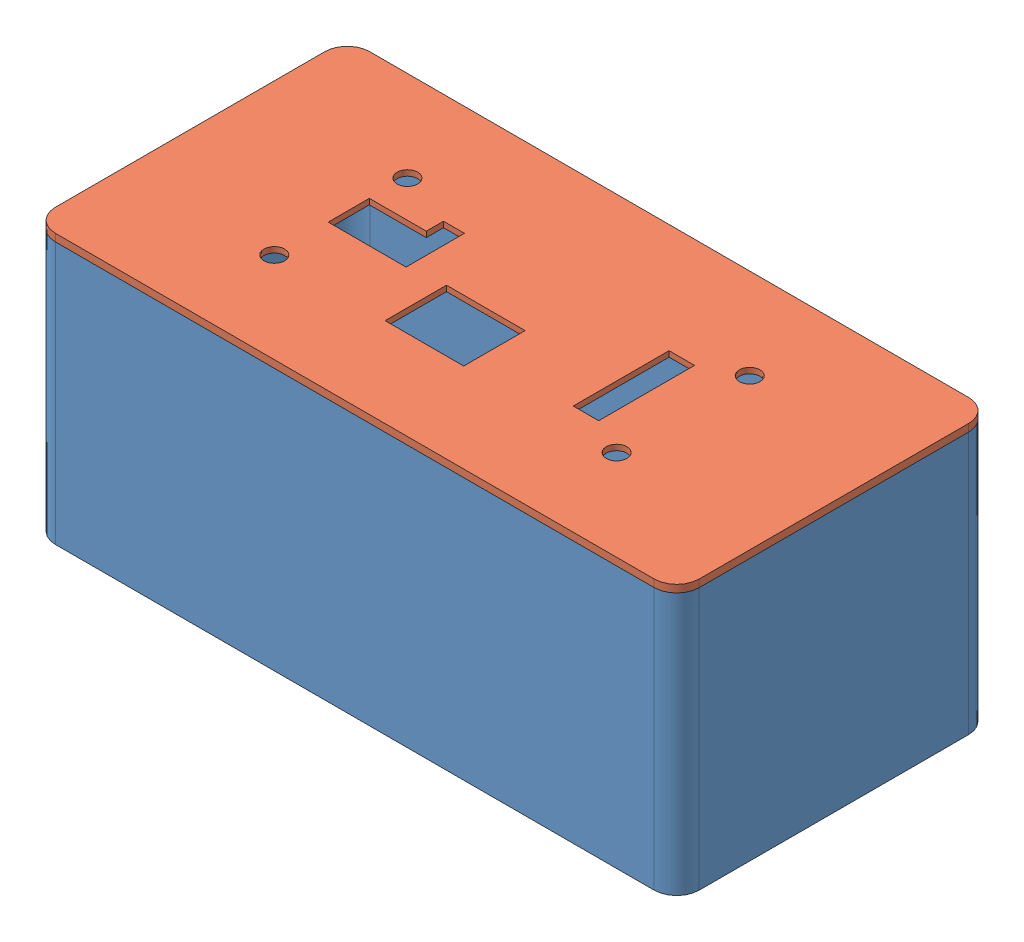
SolidWorks assembly CtrlBoard_Enclosure, configuration Default. Lengths in mm.
Overall size (86 36 42).
2 component instances, 2 part files, 4 mates.
Components (placement in the parent):
- CtrlBoard_enclosure_bottomassm-1: CtrlBoard_enclosure_bottomassm [Default] at (-11.0017 23.4167 89.7591) size (86 35 42)
- CtrlBoard_enclosure_top^CtrlBoard_Enclosure-1: CtrlBoard_enclosure_top^CtrlBoard_Enclosure [Default] at (-11.0017 58.4167 89.7591) x (1 0 0) z (0 1 0) size (86 42 2) (virtual)
Mates (geometry in assembly coordinates):
- InPlace1: in place: plane of CtrlBoard_enclosure_bottomassm-1 through (-11.0017 58.4167 89.7591) normal (0 1 0); plane of ? through (0 58.4167 0) normal (0 1 0); moOrthogonalPlaneRef_w of CtrlBoard_enclosure_bottomassm-1 through (-11.0017 58.4167 89.7591) normal (0 1 0); plane of ? through (0 58.4167 0) normal (0 0 -1); plane of CtrlBoard_enclosure_bottomassm-1 through (-11.0017 58.4167 89.7591) normal (0 1 0); plane of ? through (0 58.4167 0) normal (1 0 0); plane of CtrlBoard_enclosure_bottomassm-1 through (-11.0017 58.4167 89.7591) normal (0 1 0); unknown of CtrlBoard_enclosure_top^CtrlBoard_Enclosure-1
- Coincident1: coincident aligned: plane of CtrlBoard_enclosure_bottomassm-1; plane of CtrlBoard_enclosure_top^CtrlBoard_Enclosure-1
- Coincident2: coincident aligned: moOrthogonalPlaneRef_w of CtrlBoard_enclosure_bottomassm-1 through (-11.0017 58.4167 89.7591) normal (0 0 -1); plane of CtrlBoard_enclosure_top^CtrlBoard_Enclosure-1 through (-11.0017 58.4167 89.7591) normal (0 0 -1)
- Coincident3: coincident anti-aligned: moOrthogonalPlaneRef_w of CtrlBoard_enclosure_bottomassm-1 through (-11.0017 58.4167 89.7591) normal (-1 0 0); plane of CtrlBoard_enclosure_top^CtrlBoard_Enclosure-1 through (-11.0017 58.4167 89.7591) normal (1 0 0)
